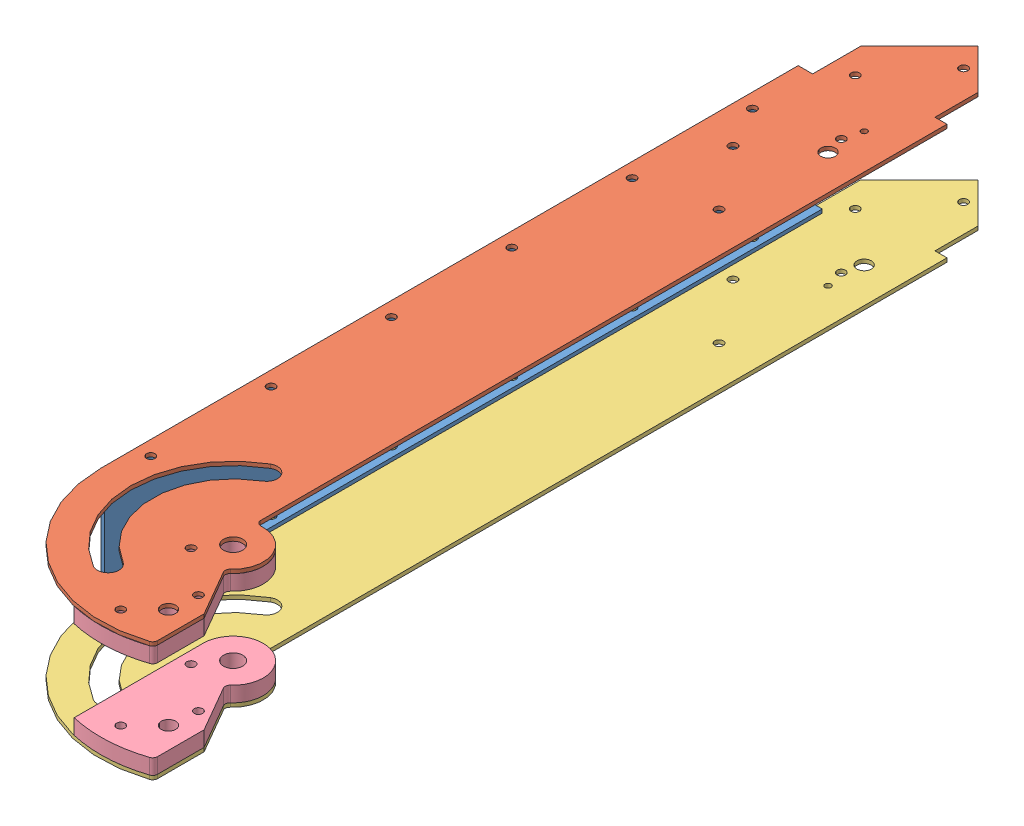
SolidWorks assembly ECM Plate, configuration Default. Lengths in mm.
Overall size (73.84 49.67 389.13).
5 component instances, 4 part files, 12 mates.
Components (placement in the parent):
- ECM Plate Aluminum - Top-1: ECM Plate Aluminum - Top [Default] at (100.2114 153.3593 78.0369) size (10 46.5 289.77)
- ECM Plate Aluminum - Right-1: ECM Plate Aluminum - Right [Default] at (154.4614 178.1968 27.2095) x (0 0 1) z (0 -1 0) size (389.13 73.84 1.59)
- ECM Plate Aluminum - Left-2: ECM Plate Aluminum - Left [Default] at (154.4614 130.1093 27.2095) x (0 0 1) z (0 -1 0) size (389.13 73.84 1.59)
- Lower Joint Reinforcer-1: Lower Joint Reinforcer [Default] at (154.4614 136.4593 27.2095) x (0 0 1) z (0 -1 0) size (67.5 31.34 6.35)
- Lower Joint Reinforcer-2: Lower Joint Reinforcer [Default] at (154.4614 176.6093 27.2095) x (0 0 1) z (0 -1 0) size (67.5 31.34 6.35)
Mates (geometry in assembly coordinates):
- Concentric4: concentric: cylinder of ECM Plate Aluminum - Top-1 through (105.4614 376.4893 353.0369) axis (0 -1 0) radius 1.75; cylinder of ECM Plate Aluminum - Right-1 through (105.4614 422.9893 353.0369) axis (0 -1 0) radius 1.75
- Concentric5: concentric: cylinder of ECM Plate Aluminum - Top-1 through (105.4614 376.4893 103.0369) axis (0 -1 0) radius 1.75; cylinder of ECM Plate Aluminum - Right-1 through (105.4614 422.9893 103.0369) axis (0 -1 0) radius 1.75
- Coincident6: coincident anti-aligned: plane of ECM Plate Aluminum - Top-1 through (100.2114 176.6093 367.8069) normal (0 1 0); plane of ECM Plate Aluminum - Right-1 through (154.4614 176.6093 27.2095) normal (0 -1 0)
- Coincident7: coincident: plane of ECM Plate Aluminum - Top-1 through (100.2114 130.1093 367.8069) normal (0 -1 0); plane of ECM Plate Aluminum - Left-2 through (154.4614 130.1093 27.2095) normal (0 1 0)
- Concentric6: concentric: cylinder of ECM Plate Aluminum - Top-1 through (105.4614 376.4893 103.0369) axis (0 -1 0) radius 1.75; cylinder of ECM Plate Aluminum - Left-2 through (105.4614 374.9018 103.0369) axis (0 -1 0) radius 1.75
- Concentric7: concentric aligned: cylinder of ECM Plate Aluminum - Top-1 through (105.4614 376.4893 353.0369) axis (0 -1 0) radius 1.75; cylinder of ECM Plate Aluminum - Left-2 through (105.4614 374.9018 353.0369) axis (0 -1 0) radius 1.75
- Coincident8: coincident: plane of ECM Plate Aluminum - Left-2 through (154.4614 130.1093 27.2095) normal (0 1 0); plane of Lower Joint Reinforcer-1 through (154.4614 130.1093 27.2095) normal (0 -1 0)
- Concentric8: concentric: cylinder of ECM Plate Aluminum - Left-2 through (154.4614 128.5218 367.8095) axis (0 1 0) radius 4; cylinder of Lower Joint Reinforcer-1 through (154.4614 130.1093 367.8095) axis (0 1 0) radius 4
- Concentric9: concentric aligned: cylinder of ECM Plate Aluminum - Left-2 through (164.2965 128.5218 404.5147) axis (0 1 0) radius 3; cylinder of Lower Joint Reinforcer-1 through (164.2965 130.1093 404.5147) axis (0 1 0) radius 3
- Coincident9: coincident: plane of ECM Plate Aluminum - Right-1 through (154.4614 176.6093 27.2095) normal (0 -1 0); plane of Lower Joint Reinforcer-2 through (154.4614 176.6093 27.2095) normal (0 1 0)
- Concentric10: concentric: cylinder of ECM Plate Aluminum - Right-1 through (154.4614 176.6093 367.8095) axis (0 1 0) radius 4; cylinder of Lower Joint Reinforcer-2 through (154.4614 170.2593 367.8095) axis (0 1 0) radius 4
- Concentric11: concentric aligned: cylinder of ECM Plate Aluminum - Right-1 through (154.4614 186.6093 414.5147) axis (0 -1 0) radius 1.75; cylinder of Lower Joint Reinforcer-2 through (154.4614 180.2593 414.5147) axis (0 -1 0) radius 1.75
